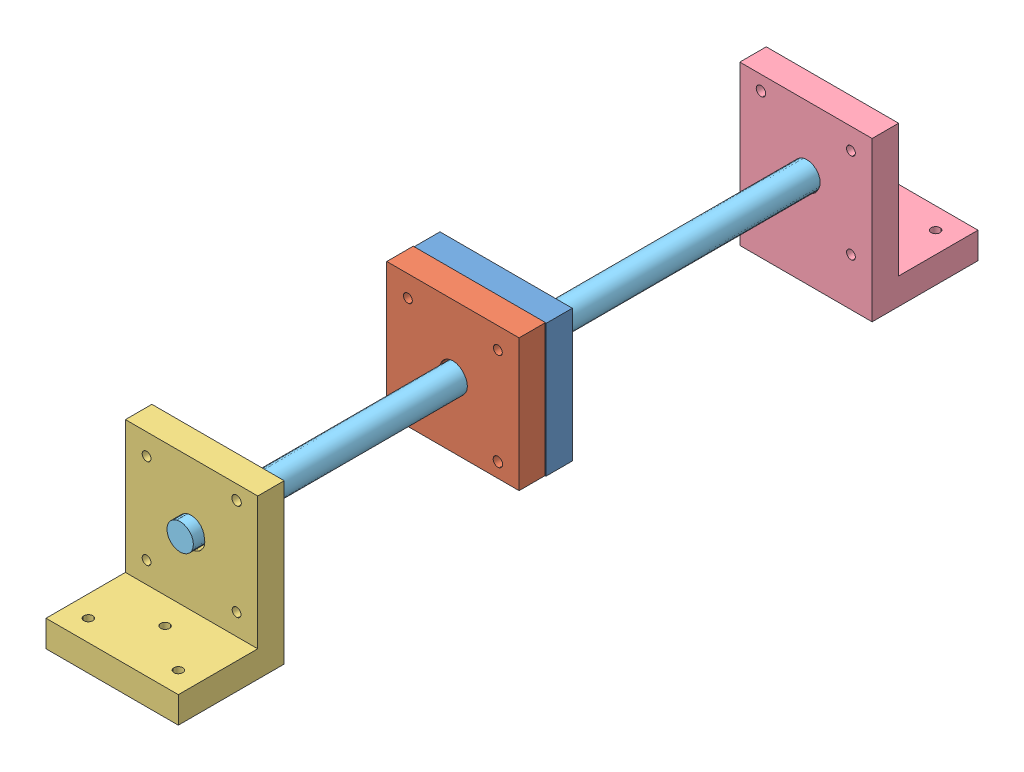
SolidWorks assembly Assem1, configuration Default. Lengths in mm.
Overall size (50.66 61.71 302.66).
5 component instances, 5 part files, 0 mates.
Components (placement in the parent):
- kare1 - Copy (12)-1: kare1 - Copy (12) [Default] at (209.5902 342.4118 -258.1093) x (1 0 0) z (0 -1 0) size (50 10 50)
- kare1 - Copy (2)-1: kare1 - Copy (2) [Default] at (209.255 342.4277 -248.3324) x (1 0 0) z (0 -1 0) size (50 10 50)
- L1 - Copy-1: L1 - Copy [Default] at (209.9111 340.7143 -138.9419) x (1 0 0) z (0 1 0) size (50 40 60)
- L1 - Copy (5)-1: L1 - Copy (5) [Default] at (209.3637 341.0807 -381.6056) x (-1 0 0) z (0 1 0) size (50 40 60)
- yboru1-1: yboru1 [Default] at (209.7307 341.8376 -384.8066) x (1 0 0) z (0 -1 0) size (10 250 10)
